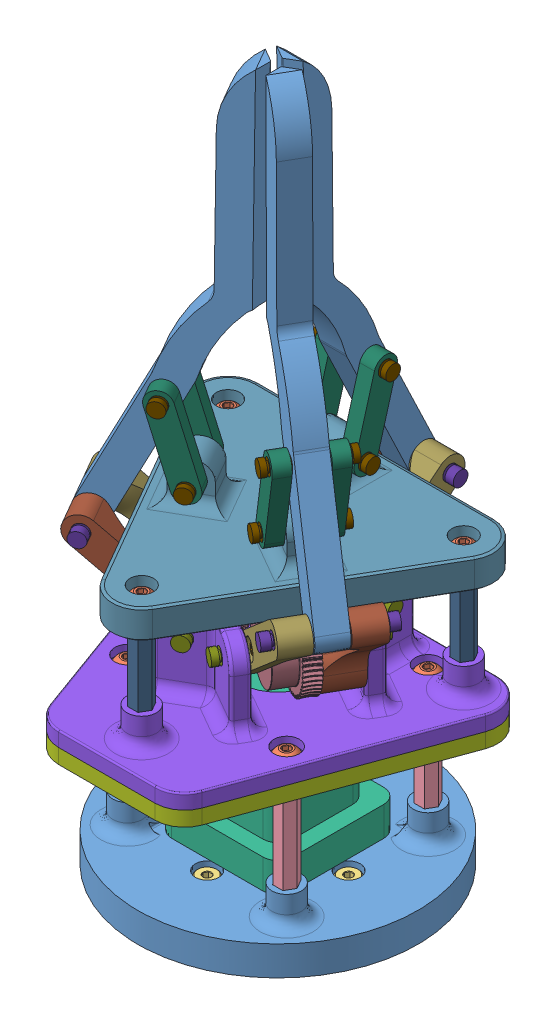
SolidWorks assembly UOM21-31A001, configuration Default. Lengths in mm.
Overall size (108.68 240.54 115).
77 component instances, 19 part files, 174 mates.
Components (placement in the parent):
- UOM21-31P001-3: UOM21-31P001 [Default] at origin size (95 20 95)
- 94500A282_316 Stainless Steel Button Head Hex Drive Screws-41: 94500A282_316 Stainless Steel Button Head Hex Drive Screws [94500A282] at (27 0.1 24) x (1 0 0) z (0 -1 0) size (7.6 7.6 18.63)
- 94500A282_316 Stainless Steel Button Head Hex Drive Screws-42: 94500A282_316 Stainless Steel Button Head Hex Drive Screws [94500A282] at (27 0.1 -24) x (1 0 0) z (0 -1 0) size (7.6 7.6 18.63)
- 94500A282_316 Stainless Steel Button Head Hex Drive Screws-39: 94500A282_316 Stainless Steel Button Head Hex Drive Screws [94500A282] at (-27 0.1 24) x (1 0 0) z (0 -1 0) size (7.6 7.6 18.63)
- 94500A282_316 Stainless Steel Button Head Hex Drive Screws-40: 94500A282_316 Stainless Steel Button Head Hex Drive Screws [94500A282] at (-27 0.1 -24) x (1 0 0) z (0 -1 0) size (7.6 7.6 18.63)
- 93070A101_Alloy Steel Low-Profile Socket Head Screw-9: 93070A101_Alloy Steel Low-Profile Socket Head Screw [93070A101] at (-24 1 0) x (0 -1 0) z (0 0 1) size (13.2 7 7)
- 93070A101_Alloy Steel Low-Profile Socket Head Screw-13: 93070A101_Alloy Steel Low-Profile Socket Head Screw [93070A101] at (0 1 -24) x (0 -1 0) z (0 0 1) size (13.2 7 7)
- 93070A101_Alloy Steel Low-Profile Socket Head Screw-14: 93070A101_Alloy Steel Low-Profile Socket Head Screw [93070A101] at (0 1 24) x (0 -1 0) z (0 0 1) size (13.2 7 7)
- 93070A101_Alloy Steel Low-Profile Socket Head Screw-12: 93070A101_Alloy Steel Low-Profile Socket Head Screw [93070A101] at (24 1 0) x (0 -1 0) z (0 0 1) size (13.2 7 7)
- 94868A189_Female Threaded Hex Standoff-14: 94868A189_Female Threaded Hex Standoff [94868A189] at (27.0577 30 24) x (0.866025 0 -0.5) z (0 1 0) size (6 6.93 40.58)
- 57545K624_Steel Worm-3: 57545K624_Steel Worm [57545K624] at (0.0289 74.746 0.05) x (-0.994537 0 -0.104387) z (0 -1 0) size (12.31 12.28 18.47)
- Stepper motor NEMA17-3: Stepper motor NEMA17 [Default] at (0.0289 70 0.05) x (-1 0 0) z (0 0 1) size (41 60 44)
- 94868A189_Female Threaded Hex Standoff-15: 94868A189_Female Threaded Hex Standoff [94868A189] at (27.0289 30 -23.95) x (0.866025 0 -0.5) z (0 -1 0) size (6 6.93 40.58)
- 94868A189_Female Threaded Hex Standoff-13: 94868A189_Female Threaded Hex Standoff [94868A189] at (-26.9711 30 -23.95) x (0.866025 0 -0.5) z (0 -1 0) size (6 6.93 40.58)
- 94868A189_Female Threaded Hex Standoff-12: 94868A189_Female Threaded Hex Standoff [94868A189] at (-26.9711 30 24.05) x (0.866025 0 -0.5) z (0 -1 0) size (6 6.93 40.58)
- UOM21-31P002-3: UOM21-31P002 [Default] at (0.0289 50 0.05) x (1 0 -0.000023) z (0.000023 0 1) size (104.02 5 90.5)
- 94500A282_316 Stainless Steel Button Head Hex Drive Screws-33: 94500A282_316 Stainless Steel Button Head Hex Drive Screws [94500A282] at (27.0289 59.5 -23.95) x (-0.837169 0 -0.546944) z (0 1 0) size (7.6 7.6 18.63)
- 94500A282_316 Stainless Steel Button Head Hex Drive Screws-37: 94500A282_316 Stainless Steel Button Head Hex Drive Screws [94500A282] at (27.0289 59.5 24.05) x (-0.837169 0 -0.546944) z (0 1 0) size (7.6 7.6 18.63)
- 94500A282_316 Stainless Steel Button Head Hex Drive Screws-38: 94500A282_316 Stainless Steel Button Head Hex Drive Screws [94500A282] at (-26.9711 59.5 24.05) x (-0.837169 0 -0.546944) z (0 1 0) size (7.6 7.6 18.63)
- 94500A282_316 Stainless Steel Button Head Hex Drive Screws-36: 94500A282_316 Stainless Steel Button Head Hex Drive Screws [94500A282] at (-26.9711 59.5 -23.95) x (0.837169 0 0.546944) z (0 1 0) size (7.6 7.6 18.63)
- UOM21-31P003-4: UOM21-31P003 [Default<As Machined>] at (0.0289 55 0.05) size (104.02 30 90.5)
- 94500A263_316 Stainless Steel Button Head Hex Drive Screws-13: 94500A263_316 Stainless Steel Button Head Hex Drive Screws [94500A263] at (15.5285 53.35 -15.4504) x (1 0 0) z (0 1 0) size (5.7 5.7 6.94)
- 94500A263_316 Stainless Steel Button Head Hex Drive Screws-15: 94500A263_316 Stainless Steel Button Head Hex Drive Screws [94500A263] at (-15.4708 53.35 15.5504) x (1 0 0) z (0 1 0) size (5.7 5.7 6.94)
- 94500A263_316 Stainless Steel Button Head Hex Drive Screws-14: 94500A263_316 Stainless Steel Button Head Hex Drive Screws [94500A263] at (15.5292 53.35 15.5496) x (1 0 0) z (0 1 0) size (5.7 5.7 6.94)
- 94500A263_316 Stainless Steel Button Head Hex Drive Screws-12: 94500A263_316 Stainless Steel Button Head Hex Drive Screws [94500A263] at (-15.4715 53.35 -15.4496) x (1 0 0) z (0 1 0) size (5.7 5.7 6.94)
- 94500A282_316 Stainless Steel Button Head Hex Drive Screws-45: 94500A282_316 Stainless Steel Button Head Hex Drive Screws [94500A282] at (40.0283 50 -23.0509) x (1 0 0) z (0 -1 0) size (7.6 7.6 18.63)
- 94500A282_316 Stainless Steel Button Head Hex Drive Screws-43: 94500A282_316 Stainless Steel Button Head Hex Drive Screws [94500A282] at (-39.9717 50 -23.0491) x (1 0 0) z (0 -1 0) size (7.6 7.6 18.63)
- 94500A282_316 Stainless Steel Button Head Hex Drive Screws-44: 94500A282_316 Stainless Steel Button Head Hex Drive Screws [94500A282] at (0.0299 50 46.24) x (1 0 0) z (0 -1 0) size (7.6 7.6 18.63)
- 94868A186_Female Threaded Hex Standoff-7: 94868A186_Female Threaded Hex Standoff [94868A186] at (-40.0306 77.5 -23.045) x (0.866025 0 -0.5) z (0 1 0) size (6 6.93 35.54)
- 94868A186_Female Threaded Hex Standoff-8: 94868A186_Female Threaded Hex Standoff [94868A186] at (0.0577 77.5 46.29) x (0.866025 0 -0.5) z (0 -1 0) size (6 6.93 35.54)
- 94868A186_Female Threaded Hex Standoff-9: 94868A186_Female Threaded Hex Standoff [94868A186] at (40.0017 77.5 -23.095) x (0.866025 0 0.5) z (0 1 0) size (6 6.93 35.54)
- UOM21-31P004-7: UOM21-31P004 [Default] at (46.3931 99.0806 10.0569) x (0.546352 -0.775886 0.315437) z (-0.5 0 0.866025) size (25.43 45.19 12.19)
- UOM21-31P005-7: UOM21-31P005 [Default] at (-34.0191 88.0989 4.1375) x (0.549252 0.773151 -0.317111) z (0.669569 -0.634222 -0.386576) size (10 9.85 54.09)
- 57545K739_Metal Worm Gear-10: 57545K739_Metal Worm Gear [57545K739] at (-0.487 77 -17.95) x (0 0.867208 -0.497946) z (-1 0 0) size (26.45 26.47 12.01)
- 57545K739_Metal Worm Gear-13: 57545K739_Metal Worm Gear [57545K739] at (15.8753 77 8.6032) x (0.262495 0.952958 0.151552) z (0.5 0 -0.866025) size (26.45 26.47 12.01)
- 57545K739_Metal Worm Gear-12: 57545K739_Metal Worm Gear [57545K739] at (-15.3017 77 9.4968) x (0.085121 -0.995158 -0.049145) z (0.5 0 0.866025) size (26.45 26.47 12.01)
- UOM21-31P004-8: UOM21-31P004 [Default] at (-31.7366 99.1978 35.1513) x (-0.549217 -0.773184 0.317091) z (-0.5 0 -0.866025) size (25.43 45.19 12.19)
- UOM21-31P004-9: UOM21-31P004 [Default] at (-14.487 99.1833 -45.0221) x (0 -0.773489 -0.633809) z (1 0 0) size (25.43 45.19 12.19)
- UOM21-31P005-8: UOM21-31P005 [Default] at (13.513 88.0917 -31.4861) x (0 0.773489 0.633809) z (0 -0.633809 0.773489) size (10 9.85 54.09)
- UOM21-31P005-9: UOM21-31P005 [Default] at (20.6342 88.0403 27.5166) x (-0.546352 0.775886 -0.315437) z (-0.671937 -0.630873 -0.387943) size (10 9.85 54.09)
- 94500A263_316 Stainless Steel Button Head Hex Drive Screws-16: 94500A263_316 Stainless Steel Button Head Hex Drive Screws [94500A263] at (14.3529 81.9082 23.3128) x (0.866025 0 0.5) z (-0.5 0 0.866025) size (5.7 5.7 6.94)
- 94500A263_316 Stainless Steel Button Head Hex Drive Screws-17: 94500A263_316 Stainless Steel Button Head Hex Drive Screws [94500A263] at (3.8976 72.0918 17.2764) x (0.866025 0 0.5) z (-0.5 0 0.866025) size (5.7 5.7 6.94)
- 94500A263_316 Stainless Steel Button Head Hex Drive Screws-18: 94500A263_316 Stainless Steel Button Head Hex Drive Screws [94500A263] at (13.013 72.069 -11.9323) x (0 0 -1) z (1 0 0) size (5.7 5.7 6.94)
- 94500A263_316 Stainless Steel Button Head Hex Drive Screws-19: 94500A263_316 Stainless Steel Button Head Hex Drive Screws [94500A263] at (13.013 81.931 -23.9677) x (0 0 -1) z (1 0 0) size (5.7 5.7 6.94)
- 94500A263_316 Stainless Steel Button Head Hex Drive Screws-20: 94500A263_316 Stainless Steel Button Head Hex Drive Screws [94500A263] at (-16.8424 72.0658 -5.2021) x (-0.742064 -0.515547 0.428431) z (-0.5 0 -0.866025) size (5.7 5.7 6.94)
- 94500A263_316 Stainless Steel Button Head Hex Drive Screws-21: 94500A263_316 Stainless Steel Button Head Hex Drive Screws [94500A263] at (-27.2609 81.9342 0.813) x (-0.742064 -0.515547 0.428431) z (-0.5 0 -0.866025) size (5.7 5.7 6.94)
- 93070A101_Alloy Steel Low-Profile Socket Head Screw-15: 93070A101_Alloy Steel Low-Profile Socket Head Screw [93070A101] at (22.6259 70.9636 6.7272) x (-0.5 0 0.866025) z (-0.801823 -0.377852 -0.462933) size (13.2 7 7)
- 93070A101_Alloy Steel Low-Profile Socket Head Screw-16: 93070A101_Alloy Steel Low-Profile Socket Head Screw [93070A101] at (-5.487 70.9823 -22.881) size (13.2 7 7)
- 93070A101_Alloy Steel Low-Profile Socket Head Screw-17: 93070A101_Alloy Steel Low-Profile Socket Head Screw [93070A101] at (-8.5277 83.0168 11.3593) x (-0.5 0 -0.866025) z (0.590736 -0.731238 -0.341061) size (13.2 7 7)
- 93070A101_Alloy Steel Low-Profile Socket Head Screw-18: 93070A101_Alloy Steel Low-Profile Socket Head Screw [93070A101] at (14.1246 83.0364 1.819) x (-0.5 0 0.866025) z (-0.801823 -0.377852 -0.462933) size (13.2 7 7)
- 93070A101_Alloy Steel Low-Profile Socket Head Screw-19: 93070A101_Alloy Steel Low-Profile Socket Head Screw [93070A101] at (-5.487 83.0177 -13.019) size (13.2 7 7)
- 93070A101_Alloy Steel Low-Profile Socket Head Screw-20: 93070A101_Alloy Steel Low-Profile Socket Head Screw [93070A101] at (-17.0736 70.986 16.2933) x (-0.5 0 -0.866025) z (0.742064 0.515547 -0.428431) size (13.2 7 7)
- UOM21-31P009-3: UOM21-31P009 [Default] at (0.0017 105 -0.001) x (-1 0 0) z (0 0 1) size (100 24 89.28)
- UOM21-31P011-21: UOM21-31P011 [Default] at (-15.2155 125.0301 20.6204) x (0.833469 0.271612 -0.481203) z (-0.235223 0.962407 0.135806) size (8 5 33)
- UOM21-31P011-20: UOM21-31P011 [Default] at (-22.7155 125.0301 7.63) x (0.833469 0.271612 -0.481203) z (-0.235223 0.962407 0.135806) size (8 5 33)
- UOM21-31P011-22: UOM21-31P011 [Default] at (23.0738 124.9953 7.2575) x (0.831056 -0.281297 0.47981) z (0.24361 0.959621 0.140649) size (8 5 33)
- UOM21-31P011-23: UOM21-31P011 [Default] at (15.5738 124.9953 20.2479) x (0.831056 -0.281297 0.47981) z (0.24361 0.959621 0.140649) size (8 5 33)
- UOM21-31P011-19: UOM21-31P011 [Default] at (9.7517 125.0311 -23.4867) x (0 -0.271334 -0.962485) z (0 0.962485 -0.271334) size (8 5 33)
- UOM21-31P011-18: UOM21-31P011 [Default] at (-5.2483 125.0311 -23.4867) x (0 -0.271334 -0.962485) z (0 0.962485 -0.271334) size (8 5 33)
- UOM21-31P006-5: UOM21-31P006 [Default] at (-22.987 77 -17.95) x (0 0 1) z (-1 0 0) size (5 5 45)
- UOM21-31P008-5: UOM21-31P008 [Default] at (17.013 99.1833 -45.0221) x (0 0 1) z (-1 0 0) size (5 5 35)
- UOM21-31P010-4: UOM21-31P010 [Default] at (12.2517 137.0621 -26.8784) x (0 1 0) z (0 0 1) size (5 25 5)
- UOM21-31P006-4: UOM21-31P006 [Default] at (4.6253 77 28.0888) x (0.866025 0 0.5) z (-0.5 0 0.866025) size (5 5 45)
- UOM21-31P006-3: UOM21-31P006 [Default] at (-26.5517 77 -9.9888) x (-0.866025 0 0.5) z (-0.5 0 -0.866025) size (5 5 45)
- UOM21-31P008-4: UOM21-31P008 [Default] at (48.1431 99.0806 7.0258) x (0.866025 0 0.5) z (-0.5 0 0.866025) size (5 5 35)
- UOM21-31P008-3: UOM21-31P008 [Default] at (-47.4866 99.1978 7.8715) x (0.866025 0 -0.5) z (0.5 0 0.866025) size (5 5 35)
- UOM21-31P010-8: UOM21-31P010 [Default] at (11.2786 113 20.6548) x (0.75 -0.5 0.433013) z (0.433013 0.866025 0.25) size (5 25 5)
- UOM21-31P010-3: UOM21-31P010 [Default] at (12.2517 113 -20.095) x (0 1 0) z (0 0 1) size (5 25 5)
- UOM21-31P010-9: UOM21-31P010 [Default] at (17.3689 136.9905 24.171) x (0.75 -0.5 0.433013) z (0.433013 0.866025 0.25) size (5 25 5)
- UOM21-31P010-7: UOM21-31P010 [Default] at (-11.0252 113 21.0878) x (0.75 -0.5 -0.433013) z (0.433013 0.866025 -0.25) size (5 25 5)
- UOM21-31P010-6: UOM21-31P010 [Default] at (-16.9058 137.0602 24.483) x (0.75 -0.5 -0.433013) z (0.433013 0.866025 -0.25) size (5 25 5)
- 94500A282_316 Stainless Steel Button Head Hex Drive Screws-46: 94500A282_316 Stainless Steel Button Head Hex Drive Screws [94500A282] at (-39.9983 103.2 -23.095) x (0.837169 0 0.546944) z (0 1 0) size (7.6 7.6 18.63)
- 94500A282_316 Stainless Steel Button Head Hex Drive Screws-47: 94500A282_316 Stainless Steel Button Head Hex Drive Screws [94500A282] at (40.0017 103.2 -23.095) x (0.837169 0 0.546944) z (0 1 0) size (7.6 7.6 18.63)
- 94500A282_316 Stainless Steel Button Head Hex Drive Screws-48: 94500A282_316 Stainless Steel Button Head Hex Drive Screws [94500A282] at (0.0017 103.2 46.187) x (0.837169 0 0.546944) z (0 1 0) size (7.6 7.6 18.63)
- Talon V2-1: Talon V2 [Default] at (-18.5605 141.9714 5.8084) x (0.86597 -0.011273 -0.499968) z (0.5 0 0.866025) size (46.77 142.04 9)
- Talon V2-2: Talon V2 [Default] at (14.5348 141.9224 13.2971) x (-0.865993 -0.00865 -0.499981) z (0.5 0 -0.866025) size (46.77 142.04 9)
- Talon V2-3: Talon V2 [Default] at (4.2517 141.9805 -18.9785) x (0 -0.010371 0.999946) z (-1 0 0) size (46.77 142.04 9)
Mates (geometry in assembly coordinates):
- Coincident1: coincident anti-aligned: plane of RoboticArm_EndEffector_Wrist_Plate-3 through (-24.75 2.3 24) normal (0 -1 0); plane of M4 x 0.7 x 16-31 through (-30.81 2.3 20.2) normal (0 1 0)
- Concentric1: concentric aligned: cylinder of RoboticArm_EndEffector_Wrist_Plate-3 through (-27 0 24) axis (0 -1 0) radius 4.3; cylinder of M4 x 0.7 x 16-31 through (-27 0.1 24) axis (0 -1 0) radius 3.8
- Coincident2: coincident anti-aligned: plane of RoboticArm_EndEffector_Wrist_Plate-3 through (-24.75 2.3 -24) normal (0 -1 0); plane of M4 x 0.7 x 16-32 through (-30.81 2.3 -27.8) normal (0 1 0)
- Concentric2: concentric aligned: cylinder of RoboticArm_EndEffector_Wrist_Plate-3 through (-27 0 -24) axis (0 -1 0) radius 4.3; cylinder of M4 x 0.7 x 16-32 through (-27 0.1 -24) axis (0 -1 0) radius 3.8
- Coincident3: coincident anti-aligned: plane of RoboticArm_EndEffector_Wrist_Plate-3 through (29.25 2.3 24) normal (0 -1 0); plane of M4 x 0.7 x 16-29 through (23.19 2.3 20.2) normal (0 1 0)
- Concentric3: concentric aligned: cylinder of RoboticArm_EndEffector_Wrist_Plate-3 through (27 0 24) axis (0 -1 0) radius 4.3; cylinder of M4 x 0.7 x 16-29 through (27 0.1 24) axis (0 -1 0) radius 3.8
- Coincident4: coincident anti-aligned: plane of RoboticArm_EndEffector_Wrist_Plate-3 through (29.25 2.3 -24) normal (0 -1 0); plane of M4 x 0.7 x 16-30 through (23.19 2.3 -27.8) normal (0 1 0)
- Concentric4: concentric aligned: cylinder of RoboticArm_EndEffector_Wrist_Plate-3 through (27 0 -24) axis (0 -1 0) radius 4.3; cylinder of M4 x 0.7 x 16-30 through (27 0.1 -24) axis (0 -1 0) radius 3.8
- Coincident5: coincident anti-aligned: plane of RoboticArm_EndEffector_Wrist_Plate-3 through (-21.75 6 0) normal (0 1 0); plane of M4 x 0.7 x 10-9 through (-20.5 6 0) normal (0 -1 0)
- Concentric5: concentric anti-aligned: cylinder of RoboticArm_EndEffector_Wrist_Plate-3 through (-24 10 0) axis (0 1 0) radius 4; cylinder of M4 x 0.7 x 10-9 through (-24 6 0) axis (0 -1 0) radius 3.5
- Coincident7: coincident anti-aligned: plane of RoboticArm_EndEffector_Wrist_Plate-3 through (2.25 6 24) normal (0 1 0); plane of M4 x 0.7 x 10-11 through (3.5 6 24) normal (0 -1 0)
- Concentric6: concentric anti-aligned: cylinder of RoboticArm_EndEffector_Wrist_Plate-3 through (0 10 24) axis (0 1 0) radius 4; cylinder of M4 x 0.7 x 10-11 through (0 6 24) axis (0 -1 0) radius 3.5
- Coincident8: coincident anti-aligned: plane of RoboticArm_EndEffector_Wrist_Plate-3 through (26.25 6 0) normal (0 1 0); plane of M4 x 0.7 x 10-12 through (27.5 6 0) normal (0 -1 0)
- Concentric7: concentric anti-aligned: cylinder of RoboticArm_EndEffector_Wrist_Plate-3 through (24 10 0) axis (0 1 0) radius 4; cylinder of M4 x 0.7 x 10-12 through (24 6 0) axis (0 -1 0) radius 3.5
- Coincident9: coincident anti-aligned: plane of RoboticArm_EndEffector_Wrist_Plate-3 through (2.25 6 -24) normal (0 1 0); plane of M4 x 0.7 x 10-10 through (3.5 6 -24) normal (0 -1 0)
- Concentric8: concentric anti-aligned: cylinder of RoboticArm_EndEffector_Wrist_Plate-3 through (0 10 -24) axis (0 1 0) radius 4; cylinder of M4 x 0.7 x 10-10 through (0 6 -24) axis (0 -1 0) radius 3.5
- Coincident10: coincident anti-aligned: plane of RoboticArm_EndEffector_Wrist_Plate-3 through (0 10 0) normal (0 1 0); plane of Female Threaded Hex Standoff - M4 x 0.7mm Thread, 40mm Long, 6mm Hex-12 through (-25.2391 10 27.05) normal (0 -1 0)
- Coincident11: coincident anti-aligned: plane of RoboticArm_EndEffector_Wrist_Plate-3 through (-25.2391 20 27.05) normal (-0.866025 0 -0.5); plane of Female Threaded Hex Standoff - M4 x 0.7mm Thread, 40mm Long, 6mm Hex-12 through (-23.507 10 24.05) normal (0.866025 0 0.5)
- Coincident12: coincident anti-aligned: plane of RoboticArm_EndEffector_Wrist_Plate-3 through (-28.7609 20 27.05) normal (0 0 -1); plane of Female Threaded Hex Standoff - M4 x 0.7mm Thread, 40mm Long, 6mm Hex-12 through (-25.2391 10 27.05) normal (0 0 1)
- Coincident13: coincident anti-aligned: plane of RoboticArm_EndEffector_Wrist_Plate-3 through (0 10 0) normal (0 1 0); plane of Female Threaded Hex Standoff - M4 x 0.7mm Thread, 40mm Long, 6mm Hex-11 through (-25.2391 10 -20.95) normal (0 -1 0)
- Coincident14: coincident anti-aligned: plane of RoboticArm_EndEffector_Wrist_Plate-3 through (-23.4782 20 -24) normal (-0.866025 0 -0.5); plane of Female Threaded Hex Standoff - M4 x 0.7mm Thread, 40mm Long, 6mm Hex-11 through (-23.507 10 -23.95) normal (0.866025 0 0.5)
- Coincident15: coincident anti-aligned: plane of RoboticArm_EndEffector_Wrist_Plate-3 through (-25.2391 20 -20.95) normal (0 0 -1); plane of Female Threaded Hex Standoff - M4 x 0.7mm Thread, 40mm Long, 6mm Hex-11 through (-25.2391 10 -20.95) normal (0 0 1)
- Coincident16: coincident anti-aligned: plane of RoboticArm_EndEffector_Wrist_Plate-3 through (0 10 0) normal (0 1 0); plane of Female Threaded Hex Standoff - M4 x 0.7mm Thread, 40mm Long, 6mm Hex-10 through (28.7609 10 -20.95) normal (0 -1 0)
- Coincident17: coincident anti-aligned: plane of RoboticArm_EndEffector_Wrist_Plate-3 through (28.7609 20 -20.95) normal (-0.866025 0 -0.5); plane of Female Threaded Hex Standoff - M4 x 0.7mm Thread, 40mm Long, 6mm Hex-10 through (30.493 10 -23.95) normal (0.866025 0 0.5)
- Coincident18: coincident anti-aligned: plane of RoboticArm_EndEffector_Wrist_Plate-3 through (25.2391 20 -20.95) normal (0 0 -1); plane of Female Threaded Hex Standoff - M4 x 0.7mm Thread, 40mm Long, 6mm Hex-10 through (28.7609 10 -20.95) normal (0 0 1)
- Coincident19: coincident anti-aligned: plane of RoboticArm_EndEffector_Wrist_Plate-3 through (0 10 0) normal (0 1 0); plane of Female Threaded Hex Standoff - M4 x 0.7mm Thread, 40mm Long, 6mm Hex-9 through (25.3257 10 21) normal (0 -1 0)
- Coincident20: coincident anti-aligned: plane of RoboticArm_EndEffector_Wrist_Plate-3 through (30.5218 20 24) normal (-0.866025 0 -0.5); plane of Female Threaded Hex Standoff - M4 x 0.7mm Thread, 40mm Long, 6mm Hex-9 through (28.7898 50 27) normal (0.866025 0 0.5)
- Coincident21: coincident anti-aligned: plane of RoboticArm_EndEffector_Wrist_Plate-3 through (28.7609 20 20.95) normal (-0.866025 0 0.5); plane of Female Threaded Hex Standoff - M4 x 0.7mm Thread, 40mm Long, 6mm Hex-9 through (30.5218 50 24) normal (0.866025 0 -0.5)
- Coincident22: coincident anti-aligned: plane of RoboticArm_EndEffector_Wrist_Plate-3 through (0 10 0) normal (0 1 0); plane of Stepper motor NEMA17-3 through (0.0289 10 0.05) normal (0 -1 0)
- Coincident24: coincident anti-aligned: plane of Female Threaded Hex Standoff - M4 x 0.7mm Thread, 40mm Long, 6mm Hex-9 through (25.3257 50 21) normal (0 1 0); plane of RoboticArm_EndEffector_Motor_Plate-3 through (0.0289 50 0.05) normal (0 -1 0)
- Coincident25: coincident anti-aligned: plane of RoboticArm_EndEffector_Motor_Plate-3 through (17.2285 51.7 -15.4504) normal (0 1 0); plane of M3 x 0.5mm thread 5mm long-9 through (12.6685 51.7 -12.6004) normal (0 -1 0)
- Concentric20: concentric aligned: cylinder of RoboticArm_EndEffector_Motor_Plate-3 through (15.5285 55 -15.4504) axis (0 1 0) radius 4.2; cylinder of M3 x 0.5mm thread 5mm long-9 through (15.5285 53.35 -15.4504) axis (0 1 0) radius 2.85
- Coincident26: coincident anti-aligned: plane of RoboticArm_EndEffector_Motor_Plate-3 through (17.2292 51.7 15.5496) normal (0 1 0); plane of M3 x 0.5mm thread 5mm long-11 through (12.6692 51.7 18.3996) normal (0 -1 0)
- Concentric21: concentric aligned: cylinder of RoboticArm_EndEffector_Motor_Plate-3 through (15.5292 55 15.5496) axis (0 1 0) radius 4.2; cylinder of M3 x 0.5mm thread 5mm long-11 through (15.5292 53.35 15.5496) axis (0 1 0) radius 2.85
- Coincident27: coincident anti-aligned: plane of RoboticArm_EndEffector_Motor_Plate-3 through (-13.7708 51.7 15.5503) normal (0 1 0); plane of M3 x 0.5mm thread 5mm long-10 through (-18.3308 51.7 18.4004) normal (0 -1 0)
- Concentric22: concentric aligned: cylinder of RoboticArm_EndEffector_Motor_Plate-3 through (-15.4708 55 15.5504) axis (0 1 0) radius 4.2; cylinder of M3 x 0.5mm thread 5mm long-10 through (-15.4708 53.35 15.5504) axis (0 1 0) radius 2.85
- Coincident28: coincident anti-aligned: plane of RoboticArm_EndEffector_Motor_Plate-3 through (-13.7715 51.7 -15.4497) normal (0 1 0); plane of M3 x 0.5mm thread 5mm long-12 through (-18.3315 51.7 -12.5996) normal (0 -1 0)
- Concentric23: concentric aligned: cylinder of RoboticArm_EndEffector_Motor_Plate-3 through (-15.4715 55 -15.4496) axis (0 1 0) radius 4.2; cylinder of M3 x 0.5mm thread 5mm long-12 through (-15.4715 53.35 -15.4496) axis (0 1 0) radius 2.85
- Coincident29: coincident anti-aligned: plane of RoboticArm_EndEffector_Motor_Plate-3 through (0.0289 55 0.05) normal (0 1 0); plane of RoboticArm_EndEffector_Mounting_Plate-4 through (0.0289 55 0.05) normal (0 -1 0)
- Concentric24: concentric aligned: cylinder of RoboticArm_EndEffector_Motor_Plate-3 through (0.0289 50 0.05) axis (0 1 0) radius 13.5; cylinder of RoboticArm_EndEffector_Mounting_Plate-4 through (0.0289 55 0.05) axis (0 1 0) radius 13.5
- Parallel2: parallel aligned: plane of RoboticArm_EndEffector_Motor_Plate-3 through (51.4351 50 -19.0308) normal (0.939693 0 0.34202); plane of RoboticArm_EndEffector_Mounting_Plate-4 through (51.436 55 -19.0298) normal (0.939693 0 0.34202)
- Coincident31: coincident anti-aligned: plane of M4 x 0.7 x 16-35 through (-21.7031 57.3 22.9526) normal (0 -1 0); plane of RoboticArm_EndEffector_Mounting_Plate-4 through (-24.7211 57.3 24.05) normal (0 1 0)
- Concentric25: concentric aligned: cylinder of M4 x 0.7 x 16-35 through (-26.9711 59.5 24.05) axis (0 1 0) radius 3.8; cylinder of RoboticArm_EndEffector_Mounting_Plate-4 through (-26.9711 60 24.05) axis (0 1 0) radius 4.3
- Coincident32: coincident anti-aligned: plane of M4 x 0.7 x 16-36 through (-32.2391 57.3 -22.8526) normal (0 -1 0); plane of RoboticArm_EndEffector_Mounting_Plate-4 through (-24.7211 57.3 -23.95) normal (0 1 0)
- Concentric26: concentric aligned: cylinder of M4 x 0.7 x 16-36 through (-26.9711 59.5 -23.95) axis (0 1 0) radius 3.8; cylinder of RoboticArm_EndEffector_Mounting_Plate-4 through (-26.9711 60 -23.95) axis (0 1 0) radius 4.3
- Coincident33: coincident anti-aligned: plane of M4 x 0.7 x 16-33 through (32.2969 57.3 -25.0474) normal (0 -1 0); plane of RoboticArm_EndEffector_Mounting_Plate-4 through (29.2789 57.3 -23.95) normal (0 1 0)
- Concentric27: concentric aligned: cylinder of M4 x 0.7 x 16-33 through (27.0289 59.5 -23.95) axis (0 1 0) radius 3.8; cylinder of RoboticArm_EndEffector_Mounting_Plate-4 through (27.0289 60 -23.95) axis (0 1 0) radius 4.3
- Coincident34: coincident anti-aligned: plane of M4 x 0.7 x 16-34 through (32.2969 57.3 22.9526) normal (0 -1 0); plane of RoboticArm_EndEffector_Mounting_Plate-4 through (29.2789 57.3 24.05) normal (0 1 0)
- Concentric28: concentric aligned: cylinder of M4 x 0.7 x 16-34 through (27.0289 59.5 24.05) axis (0 1 0) radius 3.8; cylinder of RoboticArm_EndEffector_Mounting_Plate-4 through (27.0289 60 24.05) axis (0 1 0) radius 4.3
- Concentric29: concentric anti-aligned: circle of Female Threaded Hex Standoff - M4 x 0.7mm Thread, 40mm Long, 6mm Hex-10; circle of M4 x 0.7 x 16-33
- Concentric30: concentric anti-aligned: circle of Female Threaded Hex Standoff - M4 x 0.7mm Thread, 40mm Long, 6mm Hex-11; circle of M4 x 0.7 x 16-36
- Concentric33: concentric anti-aligned: cylinder of Stepper motor NEMA17-3 through (0.0289 54 0.05) axis (0 -1 0) radius 13; cylinder of RoboticArm_EndEffector_Mounting_Plate-4 through (0.0289 55 0.05) axis (0 1 0) radius 13.5
- Parallel6: parallel aligned: plane of Stepper motor NEMA17-3 through (0.0289 20 -15.2) normal (0 0 -1); plane of RoboticArm_EndEffector_Mounting_Plate-4 through (-41.9813 55 -32.45) normal (0 0 -1)
- Concentric34: concentric aligned: cylinder of Steel Worm - 1 thread 5mm shaft-3 through (0.0289 83.746 0.05) axis (0 1 0) radius 2.5; cylinder of Stepper motor NEMA17-3 through (0.0289 50 0.05) axis (0 1 0) radius 2.5
- Coincident40: coincident anti-aligned: plane of RoboticArm_EndEffector_Mounting_Plate-4 through (0.0289 60 0.05) normal (0 1 0); plane of Female Threaded Hex Standoff - M4 x 0.7mm Thread, 35mm Long, 6mm Hex-9 through (41.7338 60 -26.095) normal (0 -1 0)
- Coincident41: coincident anti-aligned: plane of RoboticArm_EndEffector_Mounting_Plate-4 through (41.7915 70 -26.095) normal (0 0 1); plane of Female Threaded Hex Standoff - M4 x 0.7mm Thread, 35mm Long, 6mm Hex-9 through (41.7338 95 -26.095) normal (0 0 -1)
- Coincident42: coincident anti-aligned: plane of RoboticArm_EndEffector_Mounting_Plate-4 through (38.2697 70 -26.095) normal (0.866025 0 0.5); plane of Female Threaded Hex Standoff - M4 x 0.7mm Thread, 35mm Long, 6mm Hex-9 through (38.2697 95 -26.095) normal (-0.866025 0 -0.5)
- Coincident43: coincident anti-aligned: plane of RoboticArm_EndEffector_Mounting_Plate-4 through (0.0289 60 0.05) normal (0 1 0); plane of Female Threaded Hex Standoff - M4 x 0.7mm Thread, 35mm Long, 6mm Hex-8 through (1.7898 60 49.29) normal (0 -1 0)
- Coincident44: coincident anti-aligned: plane of RoboticArm_EndEffector_Mounting_Plate-4 through (-1.7321 70 49.29) normal (0 0 -1); plane of Female Threaded Hex Standoff - M4 x 0.7mm Thread, 35mm Long, 6mm Hex-8 through (1.7898 60 49.29) normal (0 0 1)
- Coincident45: coincident anti-aligned: plane of RoboticArm_EndEffector_Mounting_Plate-4 through (1.7898 70 49.29) normal (-0.866025 0 -0.5); plane of Female Threaded Hex Standoff - M4 x 0.7mm Thread, 35mm Long, 6mm Hex-8 through (3.5218 60 46.29) normal (0.866025 0 0.5)
- Coincident46: coincident anti-aligned: plane of RoboticArm_EndEffector_Mounting_Plate-4 through (0.0289 60 0.05) normal (0 1 0); plane of Female Threaded Hex Standoff - M4 x 0.7mm Thread, 35mm Long, 6mm Hex-7 through (-41.7626 60 -26.045) normal (0 -1 0)
- Coincident47: coincident anti-aligned: plane of RoboticArm_EndEffector_Mounting_Plate-4 through (-43.4947 70 -23.045) normal (0.866025 0 -0.5); plane of Female Threaded Hex Standoff - M4 x 0.7mm Thread, 35mm Long, 6mm Hex-7 through (-43.4947 95 -23.045) normal (-0.866025 0 0.5)
- Coincident48: coincident anti-aligned: plane of RoboticArm_EndEffector_Mounting_Plate-4 through (-41.7338 70 -26.095) normal (0.866025 0 0.5); plane of Female Threaded Hex Standoff - M4 x 0.7mm Thread, 35mm Long, 6mm Hex-7 through (-41.7626 95 -26.045) normal (-0.866025 0 -0.5)
- Coincident49: coincident anti-aligned: plane of RoboticArm_EndEffector_Motor_Plate-3 through (42.2783 52.2 -23.051) normal (0 -1 0); plane of M4 x 0.7 x 16-37 through (36.2183 52.2 -26.8509) normal (0 1 0)
- Concentric41: concentric aligned: cylinder of RoboticArm_EndEffector_Motor_Plate-3 through (40.0283 50 -23.0509) axis (0 -1 0) radius 4.3; cylinder of M4 x 0.7 x 16-37 through (40.0283 50 -23.0509) axis (0 -1 0) radius 3.8
- Coincident50: coincident anti-aligned: plane of RoboticArm_EndEffector_Motor_Plate-3 through (2.2799 52.2 46.2399) normal (0 -1 0); plane of M4 x 0.7 x 16-39 through (-3.7801 52.2 42.44) normal (0 1 0)
- Concentric42: concentric aligned: cylinder of RoboticArm_EndEffector_Motor_Plate-3 through (0.0299 50 46.24) axis (0 -1 0) radius 4.3; cylinder of M4 x 0.7 x 16-39 through (0.0299 50 46.24) axis (0 -1 0) radius 3.8
- Coincident51: coincident anti-aligned: plane of RoboticArm_EndEffector_Motor_Plate-3 through (-37.7217 52.2 -23.0491) normal (0 -1 0); plane of M4 x 0.7 x 16-38 through (-43.7817 52.2 -26.8491) normal (0 1 0)
- Concentric43: concentric aligned: cylinder of RoboticArm_EndEffector_Motor_Plate-3 through (-39.9717 50 -23.0491) axis (0 -1 0) radius 4.3; cylinder of M4 x 0.7 x 16-38 through (-39.9717 50 -23.0491) axis (0 -1 0) radius 3.8
- Concentric49: concentric aligned: cylinder of 57545K739_Metal Worm Gear-12 through (-18.3236 70.986 14.1282) axis (0.5 0 0.866025) radius 1.65; cylinder of UOM21-31P004-8 through (-12.5736 70.986 24.0875) axis (0.5 0 0.866025) radius 2.25
- Coincident52: coincident anti-aligned: plane of 57545K739_Metal Worm Gear-12 through (-14.0517 77 11.6618) normal (0.5 0 0.866025); plane of UOM21-31P004-8 through (-14.0507 77.0014 11.6612) normal (-0.5 0 -0.866025)
- Concentric50: concentric anti-aligned: cylinder of UOM21-31P005-7 through (-22.3017 77 -2.6276) axis (0.5 0 0.866025) radius 2.55; cylinder of 57545K739_Metal Worm Gear-12 through (-20.6517 77 0.2303) axis (-0.5 0 -0.866025) radius 2.5
- Coincident53: coincident anti-aligned: plane of UOM21-31P005-7 through (-43.4866 99.1978 14.7997) normal (0.5 0 0.866025); plane of 57545K739_Metal Worm Gear-12 through (-20.0517 77 1.2695) normal (-0.5 0 -0.866025)
- Concentric53: concentric anti-aligned: cylinder of RoboticArm_EndEffector_Mounting_Plate-4 through (-42.6357 77 -37.8472) axis (0.5 0 0.866025) radius 2.55; cylinder of 57545K739_Metal Worm Gear-12 through (-20.6517 77 0.2303) axis (-0.5 0 -0.866025) radius 2.5
- Width7: width anti-aligned: plane of UOM21-31P004-8 through (-31.7366 99.1978 35.1513) normal (0.5 0 0.866025); plane of UOM21-31P005-7 through (-45.7366 99.1978 10.9025) normal (-0.5 0 -0.866025); plane of RoboticArm_EndEffector_Mounting_Plate-4 through (-20.2211 85 -10.45) normal (-0.5 0 -0.866025); plane of RoboticArm_EndEffector_Mounting_Plate-4 through (1.0606 85 22.837) normal (0.5 0 0.866025)
- Coincident55: coincident anti-aligned: plane of 57545K739_Metal Worm Gear-10 through (-2.987 77 -17.95) normal (-1 0 0); plane of UOM21-31P004-9 through (-2.987 77 -17.95) normal (1 0 0)
- Concentric54: concentric aligned: cylinder of 57545K739_Metal Worm Gear-10 through (10.213 77 -17.95) axis (1 0 0) radius 2.5; cylinder of UOM21-31P004-9 through (-14.487 77 -17.95) axis (1 0 0) radius 2.55
- Concentric56: concentric anti-aligned: cylinder of 57545K739_Metal Worm Gear-10 through (10.213 77 -17.95) axis (1 0 0) radius 2.5; cylinder of UOM21-31P005-8 through (13.513 77 -17.95) axis (-1 0 0) radius 2.55
- Coincident56: coincident anti-aligned: plane of 57545K739_Metal Worm Gear-10 through (9.013 77 -17.95) normal (1 0 0); plane of UOM21-31P005-8 through (9.013 99.1833 -45.0221) normal (-1 0 0)
- Concentric58: concentric anti-aligned: cylinder of RoboticArm_EndEffector_Mounting_Plate-4 through (52.04 77 -17.95) axis (-1 0 0) radius 2.55; cylinder of 57545K739_Metal Worm Gear-10 through (10.213 77 -17.95) axis (1 0 0) radius 2.5
- Width8: width anti-aligned: plane of UOM21-31P004-9 through (-14.487 99.1833 -45.0221) normal (-1 0 0); plane of UOM21-31P005-8 through (13.513 99.1833 -45.0221) normal (1 0 0); plane of RoboticArm_EndEffector_Mounting_Plate-4 through (-14.7211 85 -25.45) normal (1 0 0); plane of RoboticArm_EndEffector_Mounting_Plate-4 through (13.7471 85 -9.0616) normal (-1 0 0)
- Coincident57: coincident anti-aligned: plane of UOM21-31P004-7 through (17.1253 77 6.4382) normal (-0.5 0 0.866025); plane of Worm Gear - 50 Teeth 20 Degree Pressure Angle-11 through (17.1253 77 6.4382) normal (0.5 0 -0.866025)
- Concentric59: concentric aligned: cylinder of UOM21-31P004-7 through (22.8753 77 -3.5211) axis (-0.5 0 0.866025) radius 2.55; cylinder of Worm Gear - 50 Teeth 20 Degree Pressure Angle-11 through (10.5253 77 17.8697) axis (-0.5 0 0.866025) radius 2.5
- Coincident58: coincident anti-aligned: plane of Worm Gear - 50 Teeth 20 Degree Pressure Angle-11 through (11.1253 77 16.8305) normal (-0.5 0 0.866025); plane of UOM21-31P005-9 through (34.6431 99.0806 30.4085) normal (0.5 0 -0.866025)
- Concentric61: concentric anti-aligned: cylinder of Worm Gear - 50 Teeth 20 Degree Pressure Angle-11 through (10.5253 77 17.8697) axis (-0.5 0 0.866025) radius 2.5; cylinder of UOM21-31P005-9 through (8.8753 77 20.7276) axis (0.5 0 -0.866025) radius 2.55
- Concentric63: concentric aligned: cylinder of RoboticArm_EndEffector_Mounting_Plate-4 through (42.6935 77 -37.8472) axis (-0.5 0 0.866025) radius 2.55; cylinder of Worm Gear - 50 Teeth 20 Degree Pressure Angle-11 through (10.5253 77 17.8697) axis (-0.5 0 0.866025) radius 2.5
- Width9: width aligned: plane of UOM21-31P004-7 through (46.3931 99.0806 10.0569) normal (0.5 0 -0.866025); plane of UOM21-31P005-9 through (32.3931 99.0806 34.3056) normal (-0.5 0 0.866025); plane of RoboticArm_EndEffector_Mounting_Plate-4 through (19.2471 85 -12.237) normal (0.5 0 -0.866025); plane of RoboticArm_EndEffector_Mounting_Plate-4 through (1.0606 85 22.837) normal (-0.5 0 0.866025)
- Coincident59: coincident anti-aligned: plane of UOM21-31P005-8 through (11.363 83.246 -22.8903) normal (1 0 0); plane of 94500A263_316 Stainless Steel Button Head Hex Drive Screws-19 through (11.363 79.081 -21.1077) normal (-1 0 0)
- Concentric64: concentric aligned: cylinder of UOM21-31P005-8 through (13.513 81.931 -23.9677) axis (1 0 0) radius 3.35; cylinder of 94500A263_316 Stainless Steel Button Head Hex Drive Screws-19 through (13.013 81.931 -23.9677) axis (1 0 0) radius 2.85
- Coincident60: coincident anti-aligned: plane of UOM21-31P005-8 through (11.363 73.3839 -10.8548) normal (1 0 0); plane of 94500A263_316 Stainless Steel Button Head Hex Drive Screws-18 through (11.363 69.219 -9.0723) normal (-1 0 0)
- Concentric65: concentric aligned: cylinder of UOM21-31P005-8 through (13.513 72.069 -11.9323) axis (1 0 0) radius 3.35; cylinder of 94500A263_316 Stainless Steel Button Head Hex Drive Screws-18 through (13.013 72.069 -11.9323) axis (1 0 0) radius 2.85
- Coincident61: coincident anti-aligned: plane of UOM21-31P005-9 through (14.2491 83.2272 21.3476) normal (-0.5 0 0.866025); plane of 94500A263_316 Stainless Steel Button Head Hex Drive Screws-16 through (12.7011 79.0582 20.4538) normal (0.5 0 -0.866025)
- Concentric66: concentric aligned: cylinder of UOM21-31P005-9 through (14.1029 81.9082 23.7458) axis (-0.5 0 0.866025) radius 3.35; cylinder of 94500A263_316 Stainless Steel Button Head Hex Drive Screws-16 through (14.3529 81.9082 23.3128) axis (-0.5 0 0.866025) radius 2.85
- Coincident62: coincident anti-aligned: plane of UOM21-31P005-9 through (3.7938 73.4108 15.3112) normal (-0.5 0 0.866025); plane of 94500A263_316 Stainless Steel Button Head Hex Drive Screws-17 through (2.2458 69.2418 14.4175) normal (0.5 0 -0.866025)
- Concentric67: concentric aligned: cylinder of UOM21-31P005-9 through (3.6476 72.0918 17.7094) axis (-0.5 0 0.866025) radius 3.35; cylinder of 94500A263_316 Stainless Steel Button Head Hex Drive Screws-17 through (3.8976 72.0918 17.2764) axis (-0.5 0 0.866025) radius 2.85
- Coincident63: coincident anti-aligned: plane of UOM21-31P005-7 through (-25.5022 83.2486 1.7028) normal (-0.5 0 -0.866025); plane of 94500A263_316 Stainless Steel Button Head Hex Drive Screws-21 through (-23.0411 80.9667 0.2819) normal (0.5 0 0.866025)
- Concentric68: concentric aligned: cylinder of UOM21-31P005-7 through (-27.5109 81.9342 0.38) axis (-0.5 0 -0.866025) radius 3.35; cylinder of 94500A263_316 Stainless Steel Button Head Hex Drive Screws-21 through (-27.2609 81.9342 0.813) axis (-0.5 0 -0.866025) radius 2.85
- Coincident64: coincident anti-aligned: plane of UOM21-31P005-7 through (-15.0837 73.3801 -4.3123) normal (-0.5 0 -0.866025); plane of 94500A263_316 Stainless Steel Button Head Hex Drive Screws-20 through (-12.6227 71.0982 -5.7332) normal (0.5 0 0.866025)
- Concentric69: concentric aligned: cylinder of UOM21-31P005-7 through (-17.0924 72.0658 -5.6352) axis (-0.5 0 -0.866025) radius 3.35; cylinder of 94500A263_316 Stainless Steel Button Head Hex Drive Screws-20 through (-16.8424 72.0658 -5.2021) axis (-0.5 0 -0.866025) radius 2.85
- Coincident65: coincident anti-aligned: plane of UOM21-31P004-7 through (26.3552 69.2179 3.1068) normal (0.5 0 -0.866025); plane of 93070A101_Alloy Steel Low-Profile Socket Head Screw-15 through (23.9806 74.2041 1.7358) normal (-0.5 0 0.866025)
- Concentric70: concentric anti-aligned: cylinder of UOM21-31P004-7 through (27.1259 70.9636 -1.067) axis (0.5 0 -0.866025) radius 4; cylinder of 93070A101_Alloy Steel Low-Profile Socket Head Screw-15 through (25.1259 70.9636 2.3971) axis (-0.5 0 0.866025) radius 3.5
- Coincident66: coincident anti-aligned: plane of UOM21-31P004-7 through (17.8539 81.2906 -1.8014) normal (0.5 0 -0.866025); plane of 93070A101_Alloy Steel Low-Profile Socket Head Screw-18 through (15.4793 86.2769 -3.1723) normal (-0.5 0 0.866025)
- Concentric71: concentric anti-aligned: cylinder of UOM21-31P004-7 through (18.6246 83.0364 -5.9752) axis (0.5 0 -0.866025) radius 4; cylinder of 93070A101_Alloy Steel Low-Profile Socket Head Screw-18 through (16.6246 83.0364 -2.5111) axis (-0.5 0 0.866025) radius 3.5
- Coincident67: coincident anti-aligned: plane of UOM21-31P004-8 through (-7.2635 81.2771 16.4029) normal (0.5 0 0.866025); plane of 93070A101_Alloy Steel Low-Profile Socket Head Screw-17 through (-3.8113 85.4042 14.4098) normal (-0.5 0 -0.866025)
- Concentric72: concentric anti-aligned: cylinder of UOM21-31P004-8 through (-4.0277 83.0168 19.1536) axis (0.5 0 0.866025) radius 4; cylinder of 93070A101_Alloy Steel Low-Profile Socket Head Screw-17 through (-6.0277 83.0168 15.6895) axis (-0.5 0 -0.866025) radius 3.5
- Coincident68: coincident anti-aligned: plane of UOM21-31P004-8 through (-15.8093 69.2464 21.3368) normal (0.5 0 0.866025); plane of 93070A101_Alloy Steel Low-Profile Socket Head Screw-20 through (-16.1362 73.9851 21.5256) normal (-0.5 0 -0.866025)
- Concentric73: concentric anti-aligned: cylinder of UOM21-31P004-8 through (-12.5736 70.986 24.0875) axis (0.5 0 0.866025) radius 4; cylinder of 93070A101_Alloy Steel Low-Profile Socket Head Screw-20 through (-14.5736 70.986 20.6234) axis (-0.5 0 -0.866025) radius 3.5
- Coincident69: coincident anti-aligned: plane of UOM21-31P004-9 through (-10.487 81.2774 -14.445) normal (-1 0 0); plane of 93070A101_Alloy Steel Low-Profile Socket Head Screw-16 through (-10.487 74.4823 -22.881) normal (1 0 0)
- Concentric74: concentric anti-aligned: cylinder of UOM21-31P004-9 through (-14.487 70.9823 -22.881) axis (-1 0 0) radius 4; cylinder of 93070A101_Alloy Steel Low-Profile Socket Head Screw-16 through (-10.487 70.9823 -22.881) axis (1 0 0) radius 3.5
- Coincident70: coincident anti-aligned: plane of UOM21-31P004-9 through (-10.487 81.2774 -14.445) normal (-1 0 0); plane of 93070A101_Alloy Steel Low-Profile Socket Head Screw-19 through (-10.487 86.5177 -13.019) normal (1 0 0)
- Concentric75: concentric anti-aligned: cylinder of UOM21-31P004-9 through (-14.487 83.0177 -13.019) axis (-1 0 0) radius 4; cylinder of 93070A101_Alloy Steel Low-Profile Socket Head Screw-19 through (-10.487 83.0177 -13.019) axis (1 0 0) radius 3.5
- Concentric76: concentric aligned: circle of Female Threaded Hex Standoff - M4 x 0.7mm Thread, 35mm Long, 6mm Hex-9; circle of RoboticArm_EndEffector_Palm-3
- Coincident71: coincident anti-aligned: plane of Female Threaded Hex Standoff - M4 x 0.7mm Thread, 35mm Long, 6mm Hex-9 through (41.7338 95 -26.095) normal (0 1 0); plane of RoboticArm_EndEffector_Palm-3 through (-39.9983 95 -23.095) normal (0 -1 0)
- Parallel7: parallel aligned: plane of RoboticArm_EndEffector_Mounting_Plate-4 through (-41.9813 55 -32.45) normal (0 0 -1); plane of RoboticArm_EndEffector_Palm-3 through (40.0017 95 -33.095) normal (0 0 -1)
- Concentric83: concentric anti-aligned: cylinder of RoboticArm_EndEffector_Palm-3 through (-44.2303 113 -36.4251) axis (0.5 0 0.866025) radius 2.55; cylinder of UOM21-31P011-21 through (-12.2752 113 18.9228) axis (-0.5 0 -0.866025) radius 2.55
- Concentric84: concentric anti-aligned: cylinder of RoboticArm_EndEffector_Palm-3 through (-44.2303 113 -36.4251) axis (0.5 0 0.866025) radius 2.55; cylinder of UOM21-31P011-20 through (-19.7752 113 5.9324) axis (-0.5 0 -0.866025) radius 2.55
- Coincident74: coincident anti-aligned: plane of RoboticArm_EndEffector_Palm-3 through (-19.9714 125 17.5926) normal (0.5 0 0.866025); plane of UOM21-31P011-21 through (-14.7752 113 14.5926) normal (-0.5 0 -0.866025)
- Coincident75: coincident anti-aligned: plane of RoboticArm_EndEffector_Palm-3 through (-14.5791 125 2.9324) normal (-0.5 0 -0.866025); plane of UOM21-31P011-20 through (-19.7752 113 5.9324) normal (0.5 0 0.866025)
- Parallel9: parallel aligned: line of UOM21-31P011-21 through (-17.3219 138.1466 16.063) axis (0.235223 -0.962407 -0.135806); line of UOM21-31P011-20 through (-22.3219 138.1466 7.4027) axis (0.235223 -0.962407 -0.135806)
- Concentric86: concentric aligned: cylinder of RoboticArm_EndEffector_Palm-3 through (-19.4265 113 73.8377) axis (0.5 0 -0.866025) radius 2.55; cylinder of UOM21-31P011-23 through (12.5286 113 18.4898) axis (0.5 0 -0.866025) radius 2.55
- Concentric87: concentric aligned: cylinder of RoboticArm_EndEffector_Palm-3 through (-19.4265 113 73.8377) axis (0.5 0 -0.866025) radius 2.55; cylinder of UOM21-31P011-22 through (20.0286 113 5.4994) axis (0.5 0 -0.866025) radius 2.55
- Coincident77: coincident anti-aligned: plane of RoboticArm_EndEffector_Palm-3 through (25.2248 125 8.4994) normal (0.5 0 -0.866025); plane of UOM21-31P011-22 through (20.0286 113 5.4994) normal (-0.5 0 0.866025)
- Coincident78: coincident anti-aligned: plane of RoboticArm_EndEffector_Palm-3 through (9.8325 125 11.1596) normal (-0.5 0 0.866025); plane of UOM21-31P011-23 through (15.0286 113 14.1596) normal (0.5 0 -0.866025)
- Parallel10: parallel aligned: line of UOM21-31P011-22 through (29.4431 135.8653 10.9348) axis (-0.24361 -0.959621 -0.140649); line of UOM21-31P011-23 through (24.4431 135.8653 19.5951) axis (-0.24361 -0.959621 -0.140649)
- Concentric89: concentric aligned: cylinder of RoboticArm_EndEffector_Palm-3 through (50.0017 113 -20.095) axis (-1 0 0) radius 2.55; cylinder of UOM21-31P011-18 through (-5.2483 113 -20.095) axis (-1 0 0) radius 2.55
- Concentric90: concentric aligned: cylinder of RoboticArm_EndEffector_Palm-3 through (50.0017 113 -20.095) axis (-1 0 0) radius 2.55; cylinder of UOM21-31P011-19 through (9.7517 113 -20.095) axis (-1 0 0) radius 2.55
- Coincident80: coincident anti-aligned: plane of RoboticArm_EndEffector_Palm-3 through (4.7517 125 -14.095) normal (1 0 0); plane of UOM21-31P011-19 through (4.7517 113 -20.095) normal (-1 0 0)
- Coincident81: coincident anti-aligned: plane of RoboticArm_EndEffector_Palm-3 through (-5.2483 125 -26.095) normal (-1 0 0); plane of UOM21-31P011-18 through (-5.2483 113 -20.095) normal (1 0 0)
- Parallel11: parallel aligned: line of UOM21-31P011-19 through (4.7517 135.9768 -30.7283) axis (0 -0.962485 0.271334); line of UOM21-31P011-18 through (-5.2483 135.9768 -30.7283) axis (0 -0.962485 0.271334)
- Concentric92: concentric anti-aligned: cylinder of 57545K739_Metal Worm Gear-10 through (10.213 77 -17.95) axis (1 0 0) radius 2.5; cylinder of UOM21-31P006-5 through (22.013 77 -17.95) axis (-1 0 0) radius 2.5
- Width13: width anti-aligned: plane of UOM21-31P006-5 through (-22.987 77 -17.95) normal (-1 0 0); plane of RoboticArm_EndEffector_Mounting_Plate-4 through (22.013 77 -17.95) normal (1 0 0); plane of UOM21-31P006-5 through (-20.2211 85 -10.45) normal (-1 0 0); plane of RoboticArm_EndEffector_Mounting_Plate-4 through (19.2471 85 -12.237) normal (1 0 0)
- Concentric93: concentric aligned: cylinder of Worm Gear - 50 Teeth 20 Degree Pressure Angle-11 through (10.5253 77 17.8697) axis (-0.5 0 0.866025) radius 2.5; cylinder of RoboticArm_EndEffector_Shaft 1-2 through (27.1253 77 -10.8823) axis (-0.5 0 0.866025) radius 2.5
- Width14: width anti-aligned: plane of UOM21-31P006-4 through (27.1253 77 -10.8823) normal (0.5 0 -0.866025); plane of RoboticArm_EndEffector_Mounting_Plate-4 through (4.6253 77 28.0888) normal (-0.5 0 0.866025); plane of UOM21-31P006-4 through (1.0606 85 22.837) normal (-0.5 0 0.866025); plane of RoboticArm_EndEffector_Mounting_Plate-4 through (19.2471 85 -12.237) normal (0.5 0 -0.866025)
- Concentric94: concentric aligned: cylinder of 57545K739_Metal Worm Gear-12 through (-20.6517 77 0.2303) axis (-0.5 0 -0.866025) radius 2.5; cylinder of RoboticArm_EndEffector_Shaft 1-3 through (-4.0517 77 28.9823) axis (-0.5 0 -0.866025) radius 2.5
- Width15: width anti-aligned: plane of UOM21-31P006-3 through (-26.5517 77 -9.9888) normal (-0.5 0 -0.866025); plane of RoboticArm_EndEffector_Mounting_Plate-4 through (-4.0517 77 28.9823) normal (0.5 0 0.866025); plane of UOM21-31P006-3 through (1.0606 85 22.837) normal (0.5 0 0.866025); plane of RoboticArm_EndEffector_Mounting_Plate-4 through (-20.2211 85 -10.45) normal (-0.5 0 -0.866025)
- Width16: width anti-aligned: plane of UOM21-31P008-5 through (-17.987 99.1833 -45.0221) normal (-1 0 0); plane of UOM21-31P005-8 through (17.013 99.1833 -45.0221) normal (1 0 0); plane of UOM21-31P008-5 through (13.513 99.1833 -45.0221) normal (1 0 0); plane of UOM21-31P004-9 through (-14.487 99.1833 -45.0221) normal (-1 0 0)
- Width17: width anti-aligned: plane of UOM21-31P008-4 through (48.1431 99.0806 7.0258) normal (0.5 0 -0.866025); plane of UOM21-31P005-9 through (30.6431 99.0806 37.3367) normal (-0.5 0 0.866025); plane of UOM21-31P008-4 through (32.3931 99.0806 34.3056) normal (-0.5 0 0.866025); plane of UOM21-31P004-7 through (46.3931 99.0806 10.0569) normal (0.5 0 -0.866025)
- Width18: width anti-aligned: plane of UOM21-31P008-3 through (-29.9866 99.1978 38.1823) normal (0.5 0 0.866025); plane of UOM21-31P005-7 through (-47.4866 99.1978 7.8715) normal (-0.5 0 -0.866025); plane of UOM21-31P008-3 through (-45.7366 99.1978 10.9025) normal (-0.5 0 -0.866025); plane of UOM21-31P004-8 through (-31.7366 99.1978 35.1513) normal (0.5 0 0.866025)
- Concentric98: concentric anti-aligned: cylinder of RoboticArm_EndEffector_Palm-3 through (50.0017 113 -20.095) axis (-1 0 0) radius 2.55; cylinder of RoboticArm_EndEffector_Shaft 3-3 through (-12.7483 113 -20.095) axis (1 0 0) radius 2.5
- Width19: width anti-aligned: plane of UOM21-31P010-3 through (-12.7483 113 -20.095) normal (-1 0 0); plane of UOM21-31P011-19 through (12.2517 113 -20.095) normal (1 0 0); plane of UOM21-31P010-3 through (9.7517 113 -20.095) normal (1 0 0); plane of UOM21-31P011-18 through (-10.2483 113 -20.095) normal (-1 0 0)
- Width20: width anti-aligned: plane of UOM21-31P010-4 through (12.2517 137.0621 -26.8784) normal (1 0 0); plane of UOM21-31P011-18 through (-12.7483 137.0621 -26.8784) normal (-1 0 0); plane of UOM21-31P010-4 through (-10.2483 113 -20.095) normal (-1 0 0); plane of UOM21-31P011-19 through (9.7517 113 -20.095) normal (1 0 0)
- Concentric100: concentric anti-aligned: cylinder of RoboticArm_EndEffector_Palm-3 through (-19.4265 113 73.8377) axis (0.5 0 -0.866025) radius 2.55; cylinder of RoboticArm_EndEffector_Shaft 3-2 through (23.7786 113 -0.9958) axis (-0.5 0 0.866025) radius 2.5
- Width21: width aligned: plane of UOM21-31P010-8 through (23.7786 113 -0.9958) normal (0.5 0 -0.866025); plane of UOM21-31P011-22 through (11.2786 113 20.6548) normal (-0.5 0 0.866025); plane of UOM21-31P010-8 through (22.5286 113 1.1693) normal (0.5 0 -0.866025); plane of UOM21-31P011-23 through (12.5286 113 18.4898) normal (-0.5 0 0.866025)
- Concentric102: concentric aligned: cylinder of RoboticArm_EndEffector_Palm-3 through (-44.2303 113 -36.4251) axis (0.5 0 0.866025) radius 2.55; cylinder of RoboticArm_EndEffector_Shaft 3-5 through (-23.5252 113 -0.5628) axis (0.5 0 0.866025) radius 2.5
- Width22: width anti-aligned: plane of UOM21-31P010-9 through (29.8689 136.9905 2.5204) normal (0.5 0 -0.866025); plane of UOM21-31P011-23 through (17.3689 136.9905 24.171) normal (-0.5 0 0.866025); plane of UOM21-31P010-9 through (12.5286 113 18.4898) normal (-0.5 0 0.866025); plane of UOM21-31P011-22 through (22.5286 113 1.1693) normal (0.5 0 -0.866025)
- Width23: width anti-aligned: plane of UOM21-31P010-6 through (-16.9058 137.0602 24.483) normal (0.5 0 0.866025); plane of UOM21-31P011-20 through (-29.4058 137.0602 2.8324) normal (-0.5 0 -0.866025); plane of UOM21-31P010-6 through (-22.2752 113 1.6023) normal (-0.5 0 -0.866025); plane of UOM21-31P011-21 through (-12.2752 113 18.9228) normal (0.5 0 0.866025)
- Width24: width aligned: plane of UOM21-31P010-7 through (-11.0252 113 21.0878) normal (0.5 0 0.866025); plane of UOM21-31P011-21 through (-23.5252 113 -0.5628) normal (-0.5 0 -0.866025); plane of UOM21-31P010-7 through (-12.2752 113 18.9228) normal (0.5 0 0.866025); plane of UOM21-31P011-20 through (-22.2752 113 1.6023) normal (-0.5 0 -0.866025)
- Coincident88: coincident anti-aligned: plane of RoboticArm_EndEffector_Palm-3 through (-42.2483 101 -23.095) normal (0 1 0); plane of M4 x 0.7 x 16-40 through (-45.2663 101 -21.9976) normal (0 -1 0)
- Concentric104: concentric aligned: cylinder of RoboticArm_EndEffector_Palm-3 through (-39.9983 105 -23.095) axis (0 1 0) radius 4; cylinder of M4 x 0.7 x 16-40 through (-39.9983 103.2 -23.095) axis (0 1 0) radius 3.8
- Coincident89: coincident anti-aligned: plane of RoboticArm_EndEffector_Palm-3 through (-2.2483 101 46.187) normal (0 1 0); plane of M4 x 0.7 x 16-42 through (-5.2663 101 47.2844) normal (0 -1 0)
- Concentric105: concentric aligned: cylinder of RoboticArm_EndEffector_Palm-3 through (0.0017 105 46.187) axis (0 1 0) radius 4; cylinder of M4 x 0.7 x 16-42 through (0.0017 103.2 46.187) axis (0 1 0) radius 3.8
- Coincident90: coincident anti-aligned: plane of RoboticArm_EndEffector_Palm-3 through (37.7517 101 -23.095) normal (0 1 0); plane of M4 x 0.7 x 16-41 through (34.7337 101 -21.9976) normal (0 -1 0)
- Concentric106: concentric aligned: cylinder of RoboticArm_EndEffector_Palm-3 through (40.0017 105 -23.095) axis (0 1 0) radius 4; cylinder of M4 x 0.7 x 16-41 through (40.0017 103.2 -23.095) axis (0 1 0) radius 3.8
- LimitDistance5: limit distance = 9.7205 mm: plane of RoboticArm_EndEffector_Link 3-17 through (4.7517 135.9768 -30.7283) normal (0 -0.271334 -0.962485); line of RoboticArm_EndEffector_Palm-3 through (40.0017 105 -32.095) axis (-1 0 0)
- LimitDistance6: limit distance = 9.7658 mm: plane of RoboticArm_EndEffector_Link 3-15 through (31.9431 135.8653 6.6047) normal (0.831056 -0.281297 0.47981); line of RoboticArm_EndEffector_Palm-3 through (7.7959 105 50.687) axis (0.5 0 -0.866025)
- LimitDistance7: limit distance = 9.7218 mm: plane of RoboticArm_EndEffector_Link 3-14 through (-31.4897 135.9737 6.9222) normal (-0.833469 -0.271612 0.481203); line of RoboticArm_EndEffector_Palm-3 through (-47.7925 105 -18.595) axis (0.5 0 0.866025)
- Concentric109: concentric aligned: cylinder of UOM21-31P004-8 through (-31.7366 99.1978 35.1513) axis (-0.5 0 -0.866025) radius 2.55; cylinder of UOM21-31P008-3 through (-29.9866 99.1978 38.1823) axis (-0.5 0 -0.866025) radius 2.5
- Concentric110: concentric anti-aligned: cylinder of UOM21-31P010-6 through (-29.4058 137.0602 2.8324) axis (0.5 0 0.866025) radius 2.5; cylinder of Talon V2-1 through (-20.9058 137.0602 17.5548) axis (-0.5 0 -0.866025) radius 2.5
- Concentric111: concentric aligned: cylinder of UOM21-31P008-3 through (-29.9866 99.1978 38.1823) axis (-0.5 0 -0.866025) radius 2.5; cylinder of Talon V2-1 through (-36.6484 99.1978 26.6438) axis (-0.5 0 -0.866025) radius 2.5
- Width25: width anti-aligned: plane of Talon V2-1 through (27.7913 129.1426 -10.5605) normal (0.5 0 0.866025); plane of UOM21-31P011-21 through (23.2913 129.1426 -18.3547) normal (-0.5 0 -0.866025); plane of Talon V2-1 through (-12.2752 113 18.9228) normal (0.5 0 0.866025); plane of UOM21-31P011-20 through (-22.2752 113 1.6023) normal (-0.5 0 -0.866025)
- Concentric112: concentric anti-aligned: cylinder of UOM21-31P011-21 through (-18.1558 137.0602 22.3179) axis (-0.5 0 -0.866025) radius 2.55; cylinder of UOM21-31P010-6 through (-29.4058 137.0602 2.8324) axis (0.5 0 0.866025) radius 2.5
- Concentric113: concentric aligned: cylinder of UOM21-31P008-5 through (-17.987 99.1833 -45.0221) axis (1 0 0) radius 2.5; cylinder of Talon V2-3 through (-4.7483 99.1833 -45.0221) axis (1 0 0) radius 2.5
- Concentric114: concentric aligned: cylinder of UOM21-31P010-4 through (-12.7483 137.0621 -26.8784) axis (1 0 0) radius 2.5; cylinder of Talon V2-3 through (-4.7483 137.0621 -26.8784) axis (1 0 0) radius 2.5
- Concentric115: concentric anti-aligned: cylinder of UOM21-31P011-18 through (-5.2483 137.0621 -26.8784) axis (-1 0 0) radius 2.55; cylinder of UOM21-31P010-4 through (-12.7483 137.0621 -26.8784) axis (1 0 0) radius 2.5
- Width26: width aligned: plane of Talon V2-3 through (4.2517 129.1954 29.3593) normal (1 0 0); plane of UOM21-31P011-19 through (-4.7483 129.1954 29.3593) normal (-1 0 0); plane of Talon V2-3 through (9.7517 113 -20.095) normal (1 0 0); plane of UOM21-31P011-18 through (-10.2483 113 -20.095) normal (-1 0 0)
- Concentric116: concentric anti-aligned: cylinder of UOM21-31P008-4 through (30.6431 99.0806 37.3367) axis (0.5 0 -0.866025) radius 2.5; cylinder of Talon V2-2 through (41.5254 99.0806 18.4879) axis (-0.5 0 0.866025) radius 2.5
- Concentric117: concentric aligned: cylinder of UOM21-31P010-9 through (29.8689 136.9905 2.5204) axis (-0.5 0 0.866025) radius 2.5; cylinder of Talon V2-2 through (25.8689 136.9905 9.4486) axis (-0.5 0 0.866025) radius 2.5
- Concentric118: concentric anti-aligned: cylinder of UOM21-31P011-23 through (18.6189 136.9905 22.006) axis (0.5 0 -0.866025) radius 2.55; cylinder of UOM21-31P010-9 through (29.8689 136.9905 2.5204) axis (-0.5 0 0.866025) radius 2.5
- Width27: width anti-aligned: plane of Talon V2-2 through (-22.846 129.2205 -18.6769) normal (0.5 0 -0.866025); plane of UOM21-31P011-22 through (-27.346 129.2205 -10.8827) normal (-0.5 0 0.866025); plane of Talon V2-2 through (22.5286 113 1.1693) normal (0.5 0 -0.866025); plane of UOM21-31P011-23 through (12.5286 113 18.4898) normal (-0.5 0 0.866025)
- Concentric119: concentric anti-aligned: cylinder of UOM21-31P005-7 through (-45.7366 99.1978 10.9025) axis (0.5 0 0.866025) radius 2.55; cylinder of UOM21-31P008-3 through (-29.9866 99.1978 38.1823) axis (-0.5 0 -0.866025) radius 2.5
- Concentric120: concentric aligned: cylinder of UOM21-31P004-9 through (-14.487 99.1833 -45.0221) axis (1 0 0) radius 2.55; cylinder of UOM21-31P008-5 through (-17.987 99.1833 -45.0221) axis (1 0 0) radius 2.5
- Concentric121: concentric anti-aligned: cylinder of UOM21-31P005-8 through (13.513 99.1833 -45.0221) axis (-1 0 0) radius 2.55; cylinder of UOM21-31P008-5 through (-17.987 99.1833 -45.0221) axis (1 0 0) radius 2.5
- Concentric125: concentric anti-aligned: cylinder of UOM21-31P004-7 through (46.3931 99.0806 10.0569) axis (-0.5 0 0.866025) radius 2.55; cylinder of UOM21-31P008-4 through (30.6431 99.0806 37.3367) axis (0.5 0 -0.866025) radius 2.5
- Concentric126: concentric aligned: cylinder of UOM21-31P005-9 through (32.3931 99.0806 34.3056) axis (0.5 0 -0.866025) radius 2.55; cylinder of UOM21-31P008-4 through (30.6431 99.0806 37.3367) axis (0.5 0 -0.866025) radius 2.5
